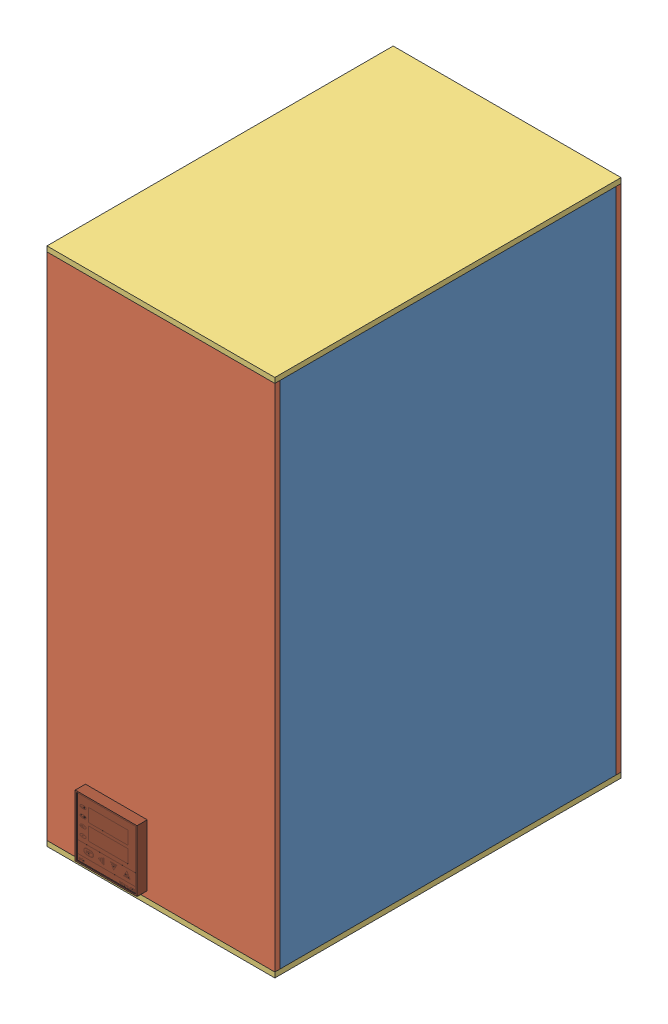
SolidWorks assembly Plastic Dryer, configuration По умолчанию. Lengths in mm.
Overall size (176.4 402.6 279.72).
49 component instances, 25 part files, 97 mates.
Components (placement in the parent):
- Wall-1: Wall [По умолчанию] at (-84.2 0 0) x (0 0 1) z (-1 0 0) size (260 394.6 4)
- Wall-2: Wall [По умолчанию] at (84.2 0 0) x (0 0 -1) z (1 0 0) size (260 394.6 4)
- Wall 3-3: Wall 3 [По умолчанию] at (0 130 130) size (176.4 394.6 4)
- Wall 3-4: Wall 3 [По умолчанию] at (0 130 -134) size (176.4 394.6 4)
- Wall4-1: Wall4 [По умолчанию] at (0 130 0) x (-1 0 0) z (0 1 0) size (176.4 268 4)
- Wall 2-1: Wall 2 [По умолчанию] at (0 -176 0) x (1 0 0) z (0 -1 0) size (168.4 260 4)
- Wall4-2: Wall4 [По умолчанию] at (0 -268.6 0) x (-1 0 0) z (0 1 0) size (176.4 268 4)
- Heater 400 W -2: Heater 400 W  [По умолчанию] at (59.625 -156 0) x (-1 0 0) z (0 0 -1) size (129.62 26 63.05)
- AC_Power_Socket-3_pin_250V_10A_AC-17.STEP-1: AC_Power_Socket-3_pin_250V_10A_AC-17.STEP [По умолчанию] at (-42.75 -239.7 -134) x (-1 0 0) z (0 0 -1) size (66.3 32.3 35.64)
  - Fuse_contact.STEP-1: Fuse_contact.STEP [По умолчанию] at (0.5 8 -20.4) x (0 1 0) z (1 0 0) size (5 15 5.6) (hidden)
    - ________fuse.STEP-1: ________fuse.STEP [По умолчанию] at origin size (4.5 6.6 2)
    - Fuse_holder.STEP-1: Fuse_holder.STEP [По умолчанию] at (0 5 0) x (0 0 -1) z (1 0 0) size (5.6 10.3 5)
  - Fuse_contact-1.STEP-1: Fuse_contact-1.STEP [По умолчанию] at (0.5 -8 -20.4) x (0 -1 0) z (-1 0 0) size (5 15 5.6) (hidden)
    - ________fuse.STEP-1: ________fuse.STEP [По умолчанию] at origin size (4.5 6.6 2)
    - Fuse_holder.STEP-1: Fuse_holder.STEP [По умолчанию] at (0 5 0) x (0 0 -1) z (1 0 0) size (5.6 10.3 5)
  - __________________________________________.STEP-1: __________________________________________.STEP [По умолчанию] at (4.9288 0 3.8) x (-1 0 0) z (0 1 0) size (13 19 24.9) (hidden)
    - ________________________.STEP-1: ________________________.STEP [По умолчанию] at (-0.0712 0 0) size (13 19 24.9)
    - Fuse Small 1A.STEP-1: Fuse Small 1A.STEP [По умолчанию] at (4.4288 -12.4 0) x (0 0 -1) z (1 0 0) size (21 5.1 5.1)
  - Case_PC.STEP-1: Case_PC.STEP [По умолчанию] at origin size (66.3 32.3 24.3)
  - _______.STEP-1: _______.STEP [По умолчанию] at (-11.6 7 -19.3) x (1 0 0) z (0 -1 0) size (5.5 18.6 2) (hidden)
  - ________GND.STEP-1: ________GND.STEP [По умолчанию] at (-15.6 0 -19.3) x (1 0 0) z (0 -1 0) size (5.5 21.6 2) (hidden)
  - _______.STEP-2: _______.STEP [По умолчанию] at (-11.6 -7 -19.3) x (1 0 0) z (0 -1 0) size (5.5 18.6 2) (hidden)
  - ______.STEP-1: ______.STEP [По умолчанию] at (-9.0137 7 -15.8) x (0 0 1) z (0 -1 0) size (10.4 5.89 6) (hidden)
  - ______.STEP-2: ______.STEP [По умолчанию] at (-18.1863 0 -15.8) x (0 0 1) z (0 1 0) size (10.4 5.89 6) (hidden)
  - _________.STEP-1: _________.STEP [По умолчанию] at (3.9 -10.25 -18.8) x (-1 0 0) z (0 -1 0) size (18 0.8 6.5) (hidden)
  - ______.STEP-3: ______.STEP [По умолчанию] at (3.0863 8 -15.8) x (0 0 1) z (0 -1 0) size (10.4 5.89 6) (hidden)
  - SWITCH KCD1-104_Default_As Machined_.STEP-1: SWITCH KCD1-104_Default_As Machined_.STEP [По умолчанию] at (14.7 0 -5.45) x (0 1 0) z (1 0 0) size (21.03 28.05 15) (hidden)
- SSR Heat Sink-1: SSR Heat Sink [Default] at (0 -239.7 -52) x (0 1 0) z (1 0 0) size (49.4 49.5 80)
- case_fan_120mm.stp-1: case_fan_120mm.stp [По умолчанию] at (-60 -192.5 -60) x (0 0 1) z (0 1 0) size (123.95 121.55 25.16)
- SSR-1: SSR [Default] at (0 -239.7 -10.5) x (-1 0 0) z (0 1 0) size (62.75 23.4 45.15)
- Plastic coil-2: Plastic coil [По умолчанию] at (42.1 0 0) x (0 0 -1) z (1 0 0) size (220 220 64.2)
- Plastic coil-3: Plastic coil [По умолчанию] at (-42.1 0 0) x (0 0 -1) z (1 0 0) size (220 220 64.2)
- RKC CONTROLLER.ipt-2: RKC CONTROLLER.ipt [По умолчанию] at (-58.4009 -211.9293 141.9248) size (47.83 47.57 107.37)
- DC 12V 1.25A-1: DC 12V 1.25A [По умолчанию] at (26.9229 -264.6 95.6551) x (-1 0 0) z (0 1 0) size (70.3 38.9 31)
- Bracket for heat sink-1: Bracket for heat sink [По умолчанию] at (0 -236.4838 -60) x (-1 0 0) z (0 0 -1) size (87.3 32.9 29)
- Corner 2 walls-1: Corner 2 walls [По умолчанию] at (-84.2 130 -130) x (0 -1 0) z (-1 0 0) size (13 18 18)
- Corner 3 walls-1: Corner 3 walls [По умолчанию] at (-84.2 -180 -130) x (0 1 0) z (1 0 0) size (22 22 22)
- Corner 3 walls-3: Corner 3 walls [По умолчанию] at (84.2 -180 -130) x (0 1 0) z (0 0 1) size (22 22 22)
- Corner 3 walls-6: Corner 3 walls [По умолчанию] at (-84.2 -264.6 -130) x (-1 0 0) z (0 1 0) size (22 22 22)
- Corner 3 walls-7: Corner 3 walls [По умолчанию] at (84.2 -264.6 -130) size (22 22 22)
- Corner 3 walls-8: Corner 3 walls [По умолчанию] at (-84.2 -264.6 130) x (0 -1 0) z (1 0 0) size (22 22 22)
- Corner 3 walls-9: Corner 3 walls [По умолчанию] at (-84.2 -180 130) x (0 0 1) z (1 0 0) size (22 22 22)
- Corner 3 walls-10: Corner 3 walls [По умолчанию] at (84.2 -264.6 130) x (0 0 1) z (-1 0 0) size (22 22 22)
- Corner 3 walls-11: Corner 3 walls [По умолчанию] at (84.2 -180 130) x (0 1 0) z (-1 0 0) size (22 22 22)
- Corner 2 walls-2: Corner 2 walls [По умолчанию] at (84.2 117 -130) x (0 1 0) z (1 0 0) size (13 18 18)
- Corner 2 walls-3: Corner 2 walls [По умолчанию] at (84.2 130 130) x (0 -1 0) z (1 0 0) size (13 18 18)
- Corner 2 walls-4: Corner 2 walls [По умолчанию] at (-84.2 117 130) x (0 1 0) z (-1 0 0) size (13 18 18)
- Bracket for heater-1: Bracket for heater [По умолчанию] at (0 -176 0) x (0 0 -1) z (0 1 0) size (121 26.12 20)
- Bracket for heater-2: Bracket for heater [По умолчанию] at (0 -176 0) x (0 0 1) z (0 1 0) size (121 26.12 20)
Mates (geometry in assembly coordinates):
- Coincident1: coincident anti-aligned: plane of SSR Heat Sink-1 through (1.3 -173.4186 -10.5) normal (0 0 1); plane of SSR-1 through (0 -239.7 -10.5) normal (0 0 -1)
- Width1: width anti-aligned: plane of SSR Heat Sink-1 through (0 -215 -52) normal (0 1 0); plane of SSR Heat Sink-1 through (0 -264.4 -52) normal (0 -1 0); plane of SSR-1 through (31.375 -262.275 12.9) normal (0 -1 0); plane of SSR-1 through (31.375 -217.125 12.9) normal (0 1 0)
- Width2: width anti-aligned: plane of SSR Heat Sink-1 through (40 -215 -60) normal (1 0 0); plane of SSR Heat Sink-1 through (-40 -215 -58.5) normal (-1 0 0); plane of SSR-1 through (-29.85 -262.275 -7.1) normal (-1 0 0); plane of SSR-1 through (29.85 -262.275 -7.1) normal (1 0 0)
- Parallel2: parallel aligned: plane of case_fan_120mm.stp-1 through (0 -180 0) normal (0 1 0)
- Parallel3: parallel aligned: plane of case_fan_120mm.stp-1 through (0 -192.5 60) normal (0 0 1)
- Parallel7: parallel aligned: plane of SSR-1 through (0 -239.7 11.95) normal (0 0 1)
- Parallel8: parallel anti-aligned: plane of Heater 400 W -2 through (59.625 -156 0) normal (0 -1 0)
- Parallel10: parallel anti-aligned: plane of SSR-1 through (31.375 -262.275 12.9) normal (0 -1 0)
- Parallel11: parallel anti-aligned: plane of assembly through (0 0 0) normal (1 0 0); plane of Wall-1 through (-84.2 0 0) normal (-1 0 0)
- Coincident16: coincident aligned: plane of Wall-1 through (-84.2 0 0) normal (0 1 0)
- Coincident18: coincident anti-aligned: plane of assembly through (0 0 0) normal (0 0 1); plane of Heater 400 W -2 through (59.625 -156 0) normal (0 0 -1)
- Coincident195: coincident anti-aligned: plane of Heater 400 W -2 through (0 -156 0) normal (-1 0 0)
- Distance4: distance = 20 mm anti-aligned: plane of Heater 400 W -2 through (59.625 -156 0) normal (0 -1 0); plane of Wall 2-1 through (0 -176 0) normal (0 1 0)
- Coincident28: coincident aligned: plane of Plastic coil^Plastic Dryer-1 through (-42.1 0 0) normal (0 1 0)
- Coincident24: coincident aligned: plane of Plastic coil^Plastic Dryer-1 through (-42.1 0 0) normal (0 1 0); plane of Plastic coil-2 through (42.1 0 0) normal (0 1 0)
- Coincident29: coincident anti-aligned: plane of Plastic coil^Plastic Dryer-1 through (-42.1 0 0) normal (0 0 -1)
- Coincident30: coincident aligned: plane of Wall-1 through (-84.2 0 0) normal (0 1 0)
- Coincident31: coincident aligned: plane of Wall-1 through (-84.2 0 0) normal (0 0 1)
- Coincident34: coincident aligned: plane of Wall-1 through (-88.2 130 -130) normal (0 1 0); plane of Wall-2 through (88.2 130 130) normal (0 1 0)
- Coincident35: coincident aligned: plane of Wall-1 through (-88.2 130 -130) normal (0 0 -1); plane of Wall-2 through (88.2 130 -130) normal (0 0 -1)
- Width6: width anti-aligned: plane of Heater 400 W -2 through (59.625 -151 25.375) normal (1 0 0); plane of case_fan_120mm.stp-1 through (-59.625 -151 25.375) normal (-1 0 0); plane of Heater 400 W -2 through (-60 -192.5 0) normal (-1 0 0); plane of case_fan_120mm.stp-1 through (60 -192.5 0) normal (1 0 0)
- Width15: width anti-aligned: plane of Heater 400 W -2 through (59.625 -151 25.375) normal (0 0 1); plane of Heater 400 W -2 through (59.625 -151 -25.375) normal (0 0 -1); plane of case_fan_120mm.stp-1 through (0 -192.5 -60) normal (0 0 -1); plane of case_fan_120mm.stp-1 through (0 -192.5 60) normal (0 0 1)
- Coincident43: coincident aligned: plane of SSR Heat Sink-1 through (30 -215 -60) normal (0 0 -1); plane of case_fan_120mm.stp-1 through (0 -192.5 -60) normal (0 0 -1)
- Coincident44: coincident anti-aligned: plane of SSR-1 through (0 -239.7 -10.5) normal (-1 0 0)
- Distance5: distance = 10 mm anti-aligned: plane of case_fan_120mm.stp-1 through (0 -205 0) normal (0 -1 0); plane of SSR Heat Sink-1 through (0 -215 -52) normal (0 1 0)
- Coincident55: coincident aligned: plane of Wall 2-1 through (0 -176 0) normal (1 0 0)
- Coincident62: coincident aligned: plane of Wall 3-4 through (0 130 -134) normal (1 0 0)
- Coincident65: coincident aligned: plane of SSR Heat Sink-1 through (0 -239.7 -52) normal (0 1 0); plane of AC_Power_Socket-3_pin_250V_10A_AC-17.STEP-1 through (-42.75 -239.7 -134) normal (0 1 0)
- Coincident80: coincident aligned: plane of Wall 3-4 through (-88.2 130 -130) normal (0 1 0); plane of Wall 3-3 through (-88.2 130 134) normal (0 1 0)
- Coincident114: coincident anti-aligned: plane of Wall4-1 through (0 130 0) normal (-1 0 0)
- Coincident124: coincident: line of Wall-1 through (-84.2 130 130) axis (0 0 -1); plane of Wall 3-4 through (-88.2 130 -130) normal (0 1 0)
- Coincident191: coincident anti-aligned: plane of Plastic coil-2 through (42.1 0 0) normal (0 0 -1)
- Distance30: distance = 10 mm anti-aligned: plane of Plastic coil-2 through (10 0 0) normal (-1 0 0)
- Distance31: distance = 10 mm aligned: plane of Plastic coil-3 through (-10 0 0) normal (1 0 0)
- Distance32: distance = 20 mm anti-aligned: plane of Heater 400 W -2 through (59.625 -130 0) normal (0 1 0); cylinder of Plastic coil-2 through (10 0 0) axis (1 0 0) radius 110
- Distance33: distance = 10 mm anti-aligned: plane of Wall-1 through (-84.2 0 0) normal (1 0 0); plane of Plastic coil-3 through (-74.2 0 0) normal (-1 0 0)
- Distance34: distance = 10 mm anti-aligned: plane of Wall-2 through (84.2 0 0) normal (-1 0 0); plane of Plastic coil-2 through (74.2 0 0) normal (1 0 0)
- Coincident198: coincident aligned: plane of Wall 3-3 through (0 130 130) normal (1 0 0)
- Coincident199: coincident anti-aligned: plane of Wall-2 through (88.2 130 -130) normal (0 0 -1); plane of Wall 3-4 through (0 130 -130) normal (0 0 1)
- Coincident200: coincident anti-aligned: plane of Wall-1 through (-88.2 130 130) normal (0 0 1); plane of Wall 3-3 through (0 130 130) normal (0 0 -1)
- Coincident201: coincident anti-aligned: plane of Wall 3-4 through (0 130 -134) normal (0 0 -1); plane of AC_Power_Socket-3_pin_250V_10A_AC-17.STEP-1/Case_PC.STEP-1 through (-15.6 -239.7 -134) normal (0 0 1)
- Coincident202: coincident anti-aligned: plane of Wall 3-3 through (0 130 134) normal (0 0 1); plane of RKC CONTROLLER.ipt-2 through (-34.4868 -235.7164 134) normal (0 0 -1)
- Coincident203: coincident aligned: plane of Wall-1 through (-88.2 130 -130) normal (0 1 0); plane of Wall4-1 through (0 130 0) normal (0 1 0)
- Coincident204: coincident aligned: plane of Wall4-1 through (0 130 0) normal (0 0 1)
- Coincident205: coincident aligned: plane of Wall4-2 through (0 -268.6 0) normal (0 0 1)
- Coincident206: coincident anti-aligned: plane of Wall4-2 through (0 -268.6 0) normal (-1 0 0)
- Coincident207: coincident anti-aligned: plane of Wall-1 through (-88.2 -264.6 -130) normal (0 -1 0); plane of Wall4-2 through (0 -264.6 0) normal (0 1 0)
- Coincident208: coincident aligned: plane of Wall 2-1 through (0 -176 0) normal (0 0 1)
- Coincident209: coincident anti-aligned: plane of Wall 2-1 through (0 -180 0) normal (0 -1 0); plane of case_fan_120mm.stp-1 through (0 -180 0) normal (0 1 0)
- Coincident210: coincident anti-aligned: plane of Wall4-2 through (0 -264.6 0) normal (0 1 0); plane of DC 12V 1.25A-1 through (26.9229 -264.6 95.6551) normal (0 -1 0)
- Width16: width anti-aligned: plane of AC_Power_Socket-3_pin_250V_10A_AC-17.STEP-1/Case_PC.STEP-1 through (-66.25 -251.1 -116) normal (-1 0 0); plane of AC_Power_Socket-3_pin_250V_10A_AC-17.STEP-1/Case_PC.STEP-1 through (-19.25 -247.2716 -116) normal (1 0 0); plane of SSR Heat Sink-1 through (-1.3 -173.4186 -52) normal (-1 0 0); plane of Wall-1 through (-84.2 0 0) normal (1 0 0)
- Coincident211: coincident anti-aligned: plane of SSR Heat Sink-1 through (30 -215 -60) normal (0 0 -1); plane of Bracket for heat sink-1 through (0 -228.7981 -60) normal (0 0 1)
- Coincident212: coincident anti-aligned: plane of SSR Heat Sink-1 through (0 -239.7 -52) normal (1 0 0); plane of Bracket for heat sink-1 through (0 -236.4838 -60) normal (-1 0 0)
- Coincident213: coincident anti-aligned: plane of Wall4-2 through (0 -264.6 0) normal (0 1 0); plane of Bracket for heat sink-1 through (-43.65 -264.6 -64) normal (0 -1 0)
- Coincident214: coincident anti-aligned: plane of Wall 3-4 through (0 130 -130) normal (0 0 1); plane of Corner 3 walls-1 through (-84.2 -202 -130) normal (0 0 -1)
- Coincident215: coincident anti-aligned: plane of Wall 2-1 through (0 -180 0) normal (0 -1 0); plane of Corner 3 walls-1 through (-84.2 -180 -130) normal (0 1 0)
- Coincident216: coincident anti-aligned: plane of Wall-1 through (-84.2 0 0) normal (1 0 0); plane of Corner 3 walls-1 through (-84.2 -180 -130) normal (-1 0 0)
- Coincident217: coincident anti-aligned: plane of Wall 2-1 through (0 -180 0) normal (0 -1 0); plane of Corner 3 walls-3 through (84.2 -180 -130) normal (0 1 0)
- Coincident218: coincident anti-aligned: plane of Wall-2 through (84.2 0 0) normal (-1 0 0); plane of Corner 3 walls-3 through (84.2 -202 -130) normal (1 0 0)
- Coincident219: coincident anti-aligned: plane of Wall 3-4 through (0 130 -130) normal (0 0 1); plane of Corner 3 walls-3 through (84.2 -180 -130) normal (0 0 -1)
- Coincident220: coincident anti-aligned: plane of Wall-1 through (-84.2 0 0) normal (1 0 0); plane of Corner 3 walls-6 through (-84.2 -264.6 -130) normal (-1 0 0)
- Coincident221: coincident anti-aligned: plane of Wall 3-4 through (0 130 -130) normal (0 0 1); plane of Corner 3 walls-6 through (-62.2 -264.6 -130) normal (0 0 -1)
- Coincident222: coincident anti-aligned: plane of Wall4-2 through (0 -264.6 0) normal (0 1 0); plane of Corner 3 walls-6 through (-84.2 -264.6 -130) normal (0 -1 0)
- Coincident223: coincident anti-aligned: plane of Wall4-2 through (0 -264.6 0) normal (0 1 0); plane of Corner 3 walls-7 through (62.2 -264.6 -130) normal (0 -1 0)
- Coincident224: coincident anti-aligned: plane of Wall 3-4 through (0 130 -130) normal (0 0 1); plane of Corner 3 walls-7 through (84.2 -264.6 -130) normal (0 0 -1)
- Coincident225: coincident anti-aligned: plane of Wall-2 through (84.2 0 0) normal (-1 0 0); plane of Corner 3 walls-7 through (84.2 -264.6 -130) normal (1 0 0)
- Coincident226: coincident anti-aligned: plane of Wall4-2 through (0 -264.6 0) normal (0 1 0); plane of Corner 3 walls-8 through (-84.2 -264.6 130) normal (0 -1 0)
- Coincident227: coincident anti-aligned: plane of Wall-1 through (-84.2 0 0) normal (1 0 0); plane of Corner 3 walls-8 through (-84.2 -264.6 130) normal (-1 0 0)
- Coincident228: coincident anti-aligned: plane of Wall 3-3 through (0 130 130) normal (0 0 -1); plane of Corner 3 walls-8 through (-84.2 -242.6 130) normal (0 0 1)
- Coincident229: coincident anti-aligned: plane of Wall 3-3 through (0 130 130) normal (0 0 -1); plane of Corner 3 walls-9 through (-84.2 -180 130) normal (0 0 1)
- Coincident232: coincident anti-aligned: plane of Wall 2-1 through (0 -180 0) normal (0 -1 0); plane of Corner 3 walls-9 through (-84.2 -180 108) normal (0 1 0)
- Coincident233: coincident anti-aligned: plane of Wall-1 through (-84.2 0 0) normal (1 0 0); plane of Corner 3 walls-9 through (-84.2 -180 130) normal (-1 0 0)
- Coincident234: coincident anti-aligned: plane of Wall 3-3 through (0 130 130) normal (0 0 -1); plane of Corner 3 walls-10 through (84.2 -264.6 130) normal (0 0 1)
- Coincident236: coincident anti-aligned: plane of Wall4-2 through (0 -264.6 0) normal (0 1 0); plane of Corner 3 walls-10 through (84.2 -264.6 108) normal (0 -1 0)
- Coincident237: coincident anti-aligned: plane of Wall 2-1 through (0 -180 0) normal (0 -1 0); plane of Corner 3 walls-11 through (84.2 -180 130) normal (0 1 0)
- Coincident238: coincident anti-aligned: plane of Wall 3-3 through (0 130 130) normal (0 0 -1); plane of Corner 3 walls-11 through (84.2 -202 130) normal (0 0 1)
- Coincident239: coincident anti-aligned: plane of Wall-2 through (84.2 0 0) normal (-1 0 0); plane of Corner 3 walls-10 through (84.2 -264.6 130) normal (1 0 0)
- Coincident240: coincident anti-aligned: plane of Wall-2 through (84.2 0 0) normal (-1 0 0); plane of Corner 3 walls-11 through (84.2 -180 130) normal (1 0 0)
- Coincident241: coincident anti-aligned: plane of Wall-1 through (-84.2 0 0) normal (1 0 0); plane of Corner 2 walls-1 through (-84.2 117 -130) normal (-1 0 0)
- Coincident242: coincident anti-aligned: plane of Wall 3-4 through (0 130 -130) normal (0 0 1); plane of Corner 2 walls-1 through (-84.2 117 -130) normal (0 0 -1)
- Coincident243: coincident anti-aligned: plane of Wall4-1 through (0 130 0) normal (0 -1 0); plane of Corner 2 walls-1 through (-84.2 130 -130) normal (0 1 0)
- Coincident244: coincident anti-aligned: plane of Wall-2 through (84.2 0 0) normal (-1 0 0); plane of Corner 2 walls-2 through (84.2 130 -130) normal (1 0 0)
- Coincident245: coincident anti-aligned: plane of Wall 3-4 through (0 130 -130) normal (0 0 1); plane of Corner 2 walls-2 through (84.2 130 -130) normal (0 0 -1)
- Coincident246: coincident anti-aligned: plane of Wall4-1 through (0 130 0) normal (0 -1 0); plane of Corner 2 walls-2 through (84.2 130 -130) normal (0 1 0)
- Coincident247: coincident anti-aligned: plane of Wall-2 through (84.2 0 0) normal (-1 0 0); plane of Corner 2 walls-3 through (84.2 117 130) normal (1 0 0)
- Coincident248: coincident anti-aligned: plane of Wall4-1 through (0 130 0) normal (0 -1 0); plane of Corner 2 walls-3 through (84.2 130 130) normal (0 1 0)
- Coincident249: coincident anti-aligned: plane of Wall-1 through (-84.2 0 0) normal (1 0 0); plane of Corner 2 walls-4 through (-84.2 130 130) normal (-1 0 0)
- Coincident251: coincident anti-aligned: plane of Wall4-1 through (0 130 0) normal (0 -1 0); plane of Corner 2 walls-4 through (-84.2 130 130) normal (0 1 0)
- Coincident252: coincident anti-aligned: plane of Wall 3-3 through (0 130 130) normal (0 0 -1); plane of Corner 2 walls-3 through (84.2 117 130) normal (0 0 1)
- Coincident253: coincident anti-aligned: plane of Wall 3-3 through (0 130 130) normal (0 0 -1); plane of Corner 2 walls-4 through (-84.2 130 130) normal (0 0 1)
- Coincident254: coincident aligned: plane of Wall 2-1 through (0 -176 0) normal (0 1 0); plane of Bracket for heater-1 through (0 -176 0) normal (0 1 0)
- Parallel13: parallel anti-aligned: plane of Bracket for heater-1 through (0 -176 0) normal (-1 0 0)
- Coincident257: coincident: point of Wall 2-1; point of Bracket for heater-1
- Coincident258: coincident anti-aligned: plane of Wall 2-1 through (0 -176 0) normal (0 1 0); plane of Bracket for heater-2 through (-39.29 -176 56.1119) normal (0 -1 0)
- Coincident259: coincident: point of Bracket for heater-1; point of Bracket for heater-2
- Coincident260: coincident anti-aligned: plane of Bracket for heater-1 through (0 -176 0) normal (-1 0 0); plane of Bracket for heater-2 through (0 -176 0) normal (1 0 0)
- Parallel14: parallel anti-aligned: plane of Wall 3-3 through (0 130 130) normal (0 0 -1); plane of DC 12V 1.25A-1 through (62.0729 -233.6 115.1051) normal (0 0 1)
